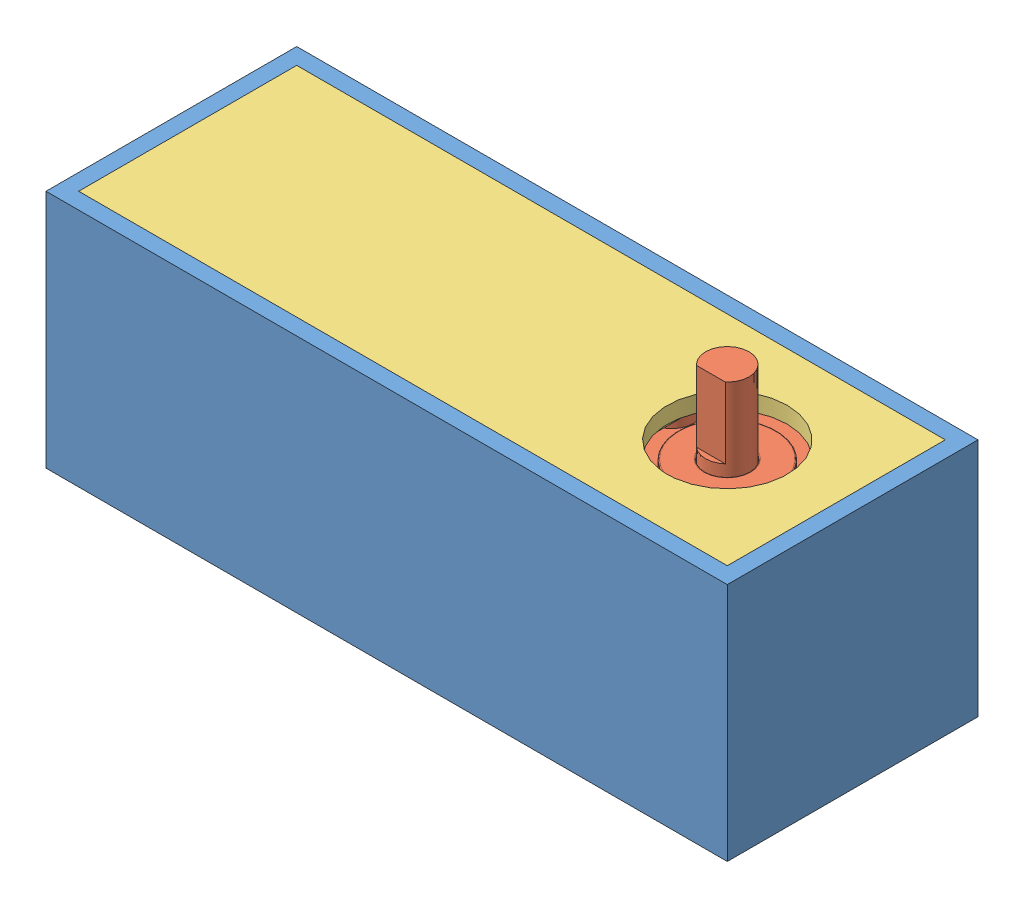
SolidWorks assembly Motor2WithCase, configuration Default. Lengths in mm.
Overall size (125 68 46).
3 component instances, 3 part files, 7 mates.
Components (placement in the parent):
- ArmBase2-1: ArmBase2 [Default] at origin size (125 56 46)
- WormGearMotor-3: WormGearMotor [Default] at (-57.7 19.5 0) x (0 0 -1) z (0 -1 0) size (40 117.2 52)
- ArmBaseCover-3: ArmBaseCover [Default] at (0 44 0) x (-1 0 0) z (0 0 1) size (119 4.5 40)
Mates (geometry in assembly coordinates):
- Coincident1: coordinate: point of ArmBase2-1
- Coincident2: coincident: plane of ArmBase2-1 through (0 7 0) normal (0 1 0); plane of WormGearMotor-3 through (39.5 7 0) normal (0 -1 0)
- Coincident3: coincident: plane of ArmBase2-1 through (59.5 44 20) normal (0 0 -1); plane of WormGearMotor-3 through (59.5 19.5 20) normal (0 0 1)
- Coincident4: coincident anti-aligned: plane of ArmBase2-1 through (59.5 44 20) normal (-1 0 0); plane of WormGearMotor-3 through (59.5 19.5 0) normal (1 0 0)
- Coincident5: coincident: plane of WormGearMotor-3 through (50.5 39.5 -14) normal (0 1 0); plane of ArmBaseCover-3 through (0 39.5 0) normal (0 -1 0)
- Coincident6: coincident: plane of ArmBase2-1 through (59.5 44 20) normal (0 0 -1); plane of ArmBaseCover-3 through (59.5 41 20) normal (0 0 1)
- Coincident7: coincident anti-aligned: plane of ArmBase2-1 through (-59.5 44 20) normal (1 0 0); plane of ArmBaseCover-3 through (-59.5 41 20) normal (-1 0 0)
